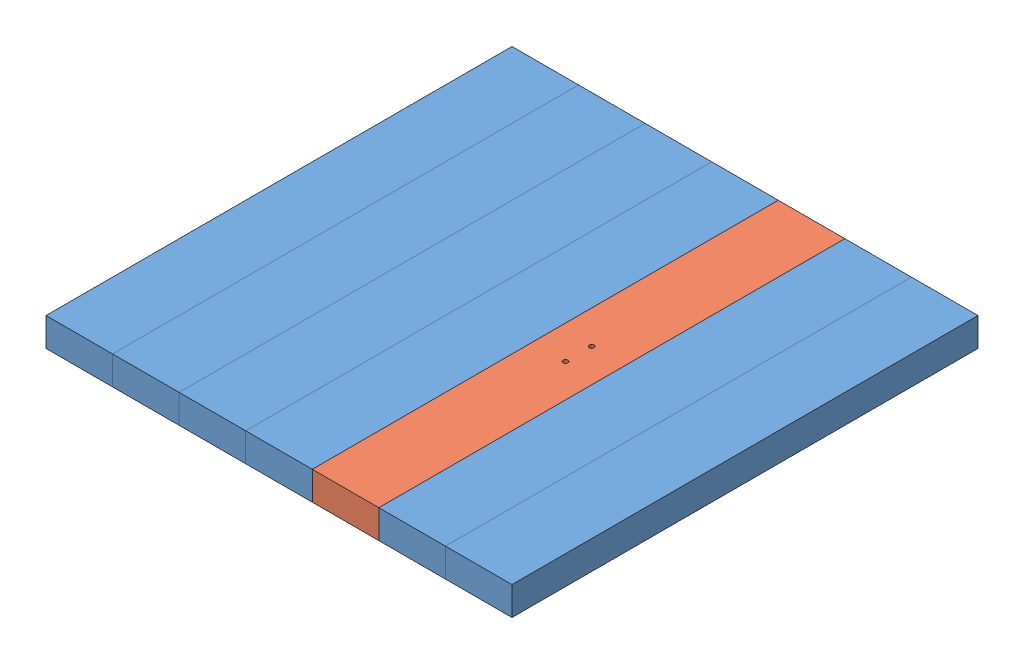
SolidWorks assembly short_side_ubolt, configuration Default. Lengths in mm.
Overall size (622.3 38.1 622.3).
7 component instances, 2 part files, 18 mates.
Components (placement in the parent):
- 24in_2x4-1: 24in_2x4 [Default] at (-374.5222 371.3202 -54.6392) size (88.9 38.1 622.3)
- 24in_2x4-2: 24in_2x4 [Default] at (-285.6222 371.3202 -54.6392) size (88.9 38.1 622.3)
- 24in_2x4-3: 24in_2x4 [Default] at (-196.7222 371.3202 -54.6392) size (88.9 38.1 622.3)
- 24in_2x4-4: 24in_2x4 [Default] at (-107.8222 371.3202 -54.6392) size (88.9 38.1 622.3)
- 24in_2x4-5: 24in_2x4 [Default] at (69.9778 371.3202 -54.6392) size (88.9 38.1 622.3)
- 24in_2x4-6: 24in_2x4 [Default] at (158.8778 371.3202 -54.6392) size (88.9 38.1 622.3)
- 24in_2x4_ubolt-1: 24in_2x4_ubolt [Default] at (-18.9222 371.3202 -54.6392) size (88.9 38.1 622.3)
Mates (geometry in assembly coordinates):
- Coincident1: coincident anti-aligned: plane of 24in_2x4-1 through (-330.0722 390.3702 567.6608) normal (1 0 0); plane of 24in_2x4-2 through (-330.0722 390.3702 567.6608) normal (-1 0 0)
- Coincident2: coincident anti-aligned: plane of 24in_2x4-2 through (-241.1722 390.3702 567.6608) normal (1 0 0); plane of 24in_2x4-3 through (-241.1722 390.3702 567.6608) normal (-1 0 0)
- Coincident3: coincident anti-aligned: plane of 24in_2x4-3 through (-152.2722 390.3702 567.6608) normal (1 0 0); plane of 24in_2x4-4 through (-152.2722 390.3702 567.6608) normal (-1 0 0)
- Coincident4: coincident anti-aligned: plane of 24in_2x4-4 through (-63.3722 390.3702 567.6608) normal (1 0 0); plane of 24in_2x4_ubolt-1 through (-63.3722 390.3702 567.6608) normal (-1 0 0)
- Coincident5: coincident anti-aligned: plane of 24in_2x4-5 through (25.5278 390.3702 567.6608) normal (-1 0 0); plane of 24in_2x4_ubolt-1 through (25.5278 390.3702 567.6608) normal (1 0 0)
- Coincident6: coincident anti-aligned: plane of 24in_2x4-5 through (114.4278 390.3702 567.6608) normal (1 0 0); plane of 24in_2x4-6 through (114.4278 390.3702 567.6608) normal (-1 0 0)
- Coincident7: coincident aligned: plane of 24in_2x4-1 through (-330.0722 352.2702 567.6608) normal (0 0 1); plane of 24in_2x4-2 through (-241.1722 352.2702 567.6608) normal (0 0 1)
- Coincident8: coincident aligned: plane of 24in_2x4-2 through (-241.1722 352.2702 567.6608) normal (0 0 1); plane of 24in_2x4-3 through (-152.2722 352.2702 567.6608) normal (0 0 1)
- Coincident9: coincident aligned: plane of 24in_2x4-3 through (-152.2722 352.2702 567.6608) normal (0 0 1); plane of 24in_2x4-4 through (-63.3722 352.2702 567.6608) normal (0 0 1)
- Coincident12: coincident aligned: plane of 24in_2x4-5 through (114.4278 352.2702 567.6608) normal (0 0 1); plane of 24in_2x4-6 through (203.3278 352.2702 567.6608) normal (0 0 1)
- Coincident13: coincident aligned: plane of 24in_2x4-1 through (-418.9722 390.3702 567.6608) normal (0 1 0); plane of 24in_2x4-2 through (-330.0722 390.3702 567.6608) normal (0 1 0)
- Coincident14: coincident aligned: plane of 24in_2x4-2 through (-330.0722 390.3702 567.6608) normal (0 1 0); plane of 24in_2x4-3 through (-241.1722 390.3702 567.6608) normal (0 1 0)
- Coincident15: coincident aligned: plane of 24in_2x4-3 through (-241.1722 390.3702 567.6608) normal (0 1 0); plane of 24in_2x4-4 through (-152.2722 390.3702 567.6608) normal (0 1 0)
- Coincident16: coincident aligned: plane of 24in_2x4-4 through (-152.2722 390.3702 567.6608) normal (0 1 0); plane of 24in_2x4_ubolt-1 through (-63.3722 390.3702 567.6608) normal (0 1 0)
- Coincident17: coincident aligned: plane of 24in_2x4-5 through (25.5278 390.3702 567.6608) normal (0 1 0); plane of 24in_2x4_ubolt-1 through (-63.3722 390.3702 567.6608) normal (0 1 0)
- Coincident18: coincident aligned: plane of 24in_2x4-5 through (25.5278 390.3702 567.6608) normal (0 1 0); plane of 24in_2x4-6 through (114.4278 390.3702 567.6608) normal (0 1 0)
- Coincident19: coincident aligned: plane of 24in_2x4-4 through (-63.3722 352.2702 567.6608) normal (0 0 1); plane of 24in_2x4_ubolt-1 through (25.5278 352.2702 567.6608) normal (0 0 1)
- Coincident20: coincident aligned: plane of 24in_2x4-5 through (114.4278 352.2702 567.6608) normal (0 0 1); plane of 24in_2x4_ubolt-1 through (25.5278 352.2702 567.6608) normal (0 0 1)
